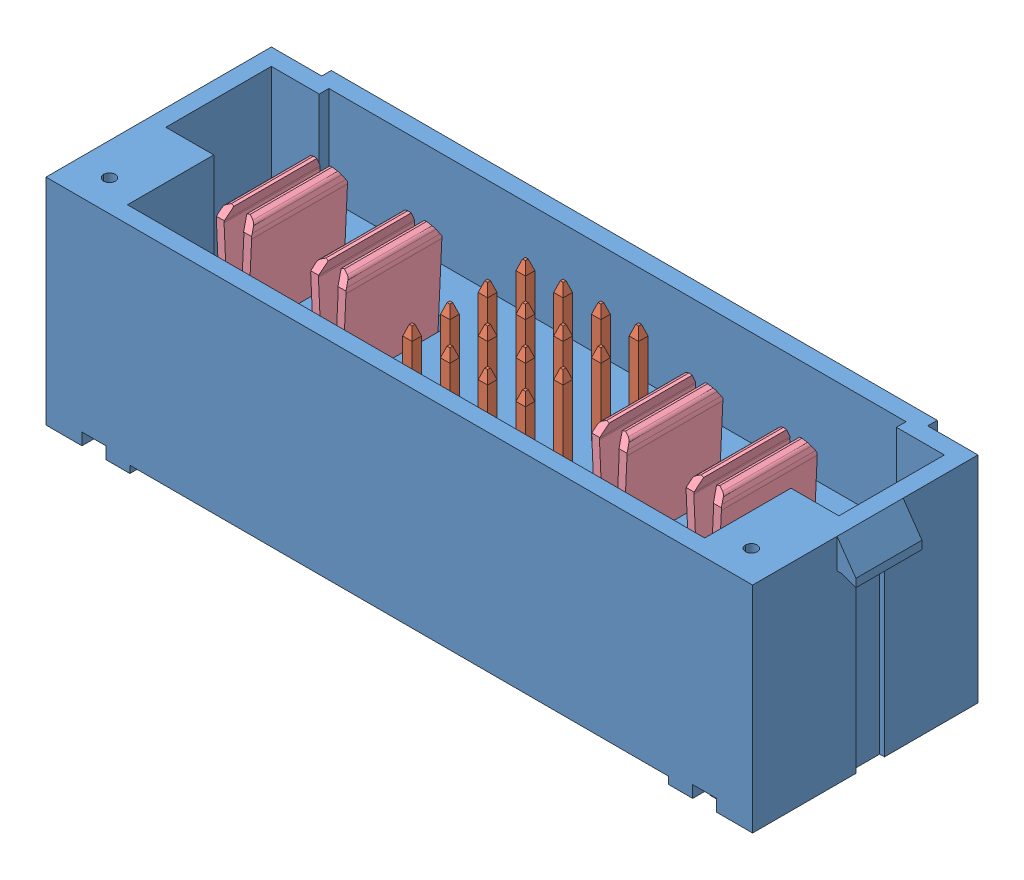
SolidWorks assembly MPTC-02-16-02-6.30-01-L-V-LC, configuration Default. Lengths in mm.
Overall size (39.44 14.43 12.45).
9 component instances, 4 part files, 3 mates.
Components (placement in the parent):
- MPTC_02_16_02_6_30_01_L_V_LC-1: MPTC_02_16_02_6_30_01_L_V_LC [Default] at (0 5.69 0) x (1 0 0) z (0 1 0) size (39.44 12.45 14.43)
  - _MPTC_02_16_02_6_30_V_LC_t_2-1: _MPTC_02_16_02_6_30_V_LC_t_2 [Default] at origin size (39.44 12.45 11.38)
  - _MPTC_02_16_02_6_30_01_V_p_4-1: _MPTC_02_16_02_6_30_01_V_p_4 [Default] at (0 0.0048 0.532) size (6.5 6.5 13.69)
  - _MPTC_01_04_01_6_30_01_L_V_c_6-1: _MPTC_01_04_01_6_30_01_L_V_c_6 [Default] at (16.255 -2.145 -4.76) x (0 1 0) z (1 0 0) size (1.42 4.7 0.25)
  - _MPTC_01_04_01_6_30_01_L_V_c_6-2: _MPTC_01_04_01_6_30_01_L_V_c_6 [Default] at (-16.255 -2.145 -4.76) x (0 1 0) z (1 0 0) size (1.42 4.7 0.25)
  - _MPTC_01_V_pp_9-1: _MPTC_01_V_pp_9 [Default] at (12.445 -2.605 -1.744) x (0 0 1) z (-1 0 0) size (13.75 7.62 2.29)
  - _MPTC_01_V_pp_9-2: _MPTC_01_V_pp_9 [Default] at (-12.445 -2.605 -1.744) x (0 0 1) z (-1 0 0) size (13.75 7.62 2.29)
  - _MPTC_01_V_pp_9-3: _MPTC_01_V_pp_9 [Default] at (7.445 -2.605 -1.744) x (0 0 1) z (-1 0 0) size (13.75 7.62 2.29)
  - _MPTC_01_V_pp_9-4: _MPTC_01_V_pp_9 [Default] at (-7.445 -2.605 -1.744) x (0 0 1) z (-1 0 0) size (13.75 7.62 2.29)
Mates (geometry in assembly coordinates):
- Coincident1: coincident: plane of ? through (7.8666 0 0) normal (0 -1 0)
- Coincident2: coincident: plane of ? through (7.8666 5.69 0) normal (0 0 -1)
- Coincident3: coincident: plane of MPTC_02_16_02_6_30_01_L_V_LC-1/_MPTC_02_16_02_6_30_V_LC_t_2-1 through (0 5.69 0) normal (1 0 0)
